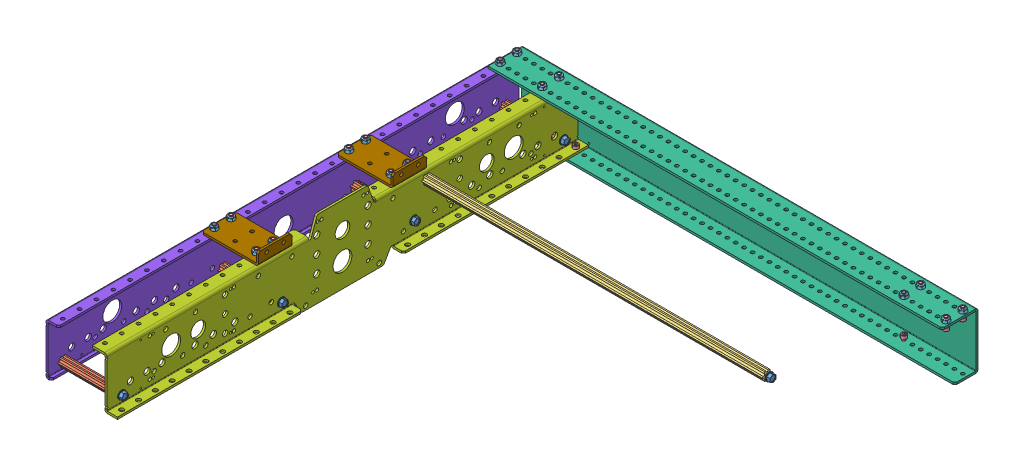
SolidWorks assembly AM14U3Square_Frame_Half, configuration Default. Lengths in mm.
Overall size (697.74 116.33 715.14).
56 component instances, 9 part files, 121 mates.
Components (placement in the parent):
- ThreadRollingScrew_0.25-20x0.75-1: ThreadRollingScrew_0.25-20x0.75 [FHTS 0.25-20-G-0.75-C] at (-600.075 -67.437 693.039) x (-1 0 0) z (0 0.924225 0.381849) size (24.64 12.19 12.19)
- ThreadRollingScrew_0.25-20x0.75-4: ThreadRollingScrew_0.25-20x0.75 [FHTS 0.25-20-G-0.75-C] at (-600.075 -67.437 26.035) x (-1 0 0) z (0 0.717495 0.696564) size (24.64 12.19 12.19)
- ThreadRollingScrew_0.25-20x0.75-5: ThreadRollingScrew_0.25-20x0.75 [FHTS 0.25-20-G-0.75-C] at (-692.15 -67.437 26.162) size (24.64 12.19 12.19)
- ThreadRollingScrew_0.25-20x0.75-7: ThreadRollingScrew_0.25-20x0.75 [FHTS 0.25-20-G-0.75-C] at (-603.25 -15.24 232.537) x (1 0 0) z (0 0.687398 0.726281) size (24.64 12.19 12.19)
- ThreadRollingScrew_0.25-20x0.75-9: ThreadRollingScrew_0.25-20x0.75 [FHTS 0.25-20-G-0.75-C] at (-692.15 -67.437 692.912) size (24.64 12.19 12.19)
- ThreadRollingScrew_0.25-20x0.75-10: ThreadRollingScrew_0.25-20x0.75 [FHTS 0.25-20-G-0.75-C] at (-82.55 -15.24 232.537) x (-1 0 0) z (0 0.525103 -0.851039) size (24.64 12.19 12.19)
- 500Churro_3.375-1: 500Churro_3.375 [Default] at (-603.25 -67.437 26.162) x (0 -0.866025 0.5) z (-1 0 0) size (14.66 12.7 85.72)
- 500Churro_3.375-2: 500Churro_3.375 [Default] at (-603.25 -67.437 692.912) x (0 -0.866025 0.5) z (-1 0 0) size (14.66 12.7 85.72)
- 500Churro_cut_20.25-1: 500Churro_cut_20.25 [Default] at (-85.725 -15.24 232.537) x (0 0 -1) z (-1 0 0) size (14.66 12.7 514.35)
- Screw_SHCS_10-32x0.5-19: Screw_SHCS_10-32x0.5 [HX-SHCS 0.19-32x1.375x1-C] at (-679.45 -11.176 42.037) x (0 1 0) z (0.542711 0 0.839919) size (17.53 7.94 7.94)
- Screw_SHCS_10-32x0.5-20: Screw_SHCS_10-32x0.5 [HX-SHCS 0.19-32x1.375x1-C] at (-679.45 -11.176 16.637) x (0 1 0) z (0.127767 0 0.991804) size (17.53 7.94 7.94)
- Screw_SHCS_10-32x0.5-21: Screw_SHCS_10-32x0.5 [HX-SHCS 0.19-32x1.375x1-C] at (-615.95 -11.176 16.637) x (0 1 0) z (0 0 1) size (17.53 7.94 7.94)
- Screw_SHCS_10-32x0.5-22: Screw_SHCS_10-32x0.5 [HX-SHCS 0.19-32x1.375x1-C] at (-615.95 -11.176 42.037) x (0 1 0) z (0.337423 0 -0.941353) size (17.53 7.94 7.94)
- Screw_SHCS_10-32x0.5-23: Screw_SHCS_10-32x0.5 [HX-SHCS 0.19-32x1.375x1-C] at (-590.55 -72.898 16.637) x (0 -1 0) z (0.717151 0 -0.696918) size (17.53 7.94 7.94)
- Screw_SHCS_10-32x0.5-24: Screw_SHCS_10-32x0.5 [HX-SHCS 0.19-32x1.375x1-C] at (-6.35 -11.176 16.637) x (0 1 0) z (0.222581 0 0.974914) size (17.53 7.94 7.94)
- Screw_SHCS_10-32x0.5-25: Screw_SHCS_10-32x0.5 [HX-SHCS 0.19-32x1.375x1-C] at (-6.35 -11.176 42.037) x (0 1 0) z (0.81526 0 0.579096) size (17.53 7.94 7.94)
- Screw_SHCS_10-32x0.5-26: Screw_SHCS_10-32x0.5 [HX-SHCS 0.19-32x1.375x1-C] at (-69.85 -11.176 16.637) x (0 1 0) z (0 0 1) size (17.53 7.94 7.94)
- Screw_SHCS_10-32x0.5-27: Screw_SHCS_10-32x0.5 [HX-SHCS 0.19-32x1.375x1-C] at (-69.85 -11.176 42.037) x (0 1 0) z (0.111454 0 0.99377) size (17.53 7.94 7.94)
- Screw_SHCS_10-32x0.5-28: Screw_SHCS_10-32x0.5 [HX-SHCS 0.19-32x1.375x1-C] at (-95.25 -73.406 16.637) x (0 -1 0) z (0.007214 0 0.999974) size (17.53 7.94 7.94)
- NylockNut_10-32-19: NylockNut_10-32 [Default] at (-679.45 0 42.037) x (0.996106 0 -0.088165) z (0 1 0) size (10.18 11.01 7.1)
- NylockNut_10-32-21: NylockNut_10-32 [Default] at (-679.45 0 16.637) x (1 0 0) z (0 1 0) size (10.18 11.01 7.1)
- NylockNut_10-32-22: NylockNut_10-32 [Default] at (-615.95 0 42.037) x (1 0 0) z (0 1 0) size (10.18 11.01 7.1)
- NylockNut_10-32-23: NylockNut_10-32 [Default] at (-615.95 0 16.637) x (-0.398852 0 -0.917015) z (0 1 0) size (10.18 11.01 7.1)
- NylockNut_10-32-25: NylockNut_10-32 [Default] at (-69.85 0 42.037) x (1 0 0) z (0 1 0) size (10.18 11.01 7.1)
- NylockNut_10-32-26: NylockNut_10-32 [Default] at (-69.85 0 16.637) x (1 0 0) z (0 1 0) size (10.18 11.01 7.1)
- NylockNut_10-32-27: NylockNut_10-32 [Default] at (-6.35 0 42.037) x (1 0 0) z (0 1 0) size (10.18 11.01 7.1)
- NylockNut_10-32-28: NylockNut_10-32 [Default] at (-6.35 0 16.637) x (1 0 0) z (0 1 0) size (10.18 11.01 7.1)
- NylockNut_10-32-29: NylockNut_10-32 [Default] at (-95.25 -84.582 16.637) x (1 0 0) z (0 -1 0) size (10.18 11.01 7.1)
- NylockNut_10-32-30: NylockNut_10-32 [Default] at (-590.55 -84.582 16.637) x (1 0 0) z (0 -1 0) size (10.18 11.01 7.1)
- Screw_SHCS_10-32x0.5-29: Screw_SHCS_10-32x0.5 [HX-SHCS 0.19-32x1.375x1-C] at (-679.45 -11.176 245.237) x (0 1 0) z (0.717626 0 0.696429) size (17.53 7.94 7.94)
- Screw_SHCS_10-32x0.5-30: Screw_SHCS_10-32x0.5 [HX-SHCS 0.19-32x1.375x1-C] at (-679.45 -11.176 270.637) x (0 1 0) z (-0.597439 0 0.801914) size (17.53 7.94 7.94)
- Screw_SHCS_10-32x0.5-31: Screw_SHCS_10-32x0.5 [HX-SHCS 0.19-32x1.375x1-C] at (-615.95 -11.176 245.237) x (0 1 0) z (0.931086 0 -0.3648) size (17.53 7.94 7.94)
- Screw_SHCS_10-32x0.5-32: Screw_SHCS_10-32x0.5 [HX-SHCS 0.19-32x1.375x1-C] at (-615.95 -11.176 270.637) x (0 1 0) z (0.782299 0 0.622903) size (17.53 7.94 7.94)
- Screw_SHCS_10-32x0.5-33: Screw_SHCS_10-32x0.5 [HX-SHCS 0.19-32x1.375x1-C] at (-615.95 -11.176 448.437) x (0 1 0) z (0 0 1) size (17.53 7.94 7.94)
- Screw_SHCS_10-32x0.5-34: Screw_SHCS_10-32x0.5 [HX-SHCS 0.19-32x1.375x1-C] at (-615.95 -11.176 473.837) x (0 1 0) z (0 0 1) size (17.53 7.94 7.94)
- Screw_SHCS_10-32x0.5-35: Screw_SHCS_10-32x0.5 [HX-SHCS 0.19-32x1.375x1-C] at (-679.45 -11.176 448.437) x (0 1 0) z (0 0 1) size (17.53 7.94 7.94)
- Screw_SHCS_10-32x0.5-36: Screw_SHCS_10-32x0.5 [HX-SHCS 0.19-32x1.375x1-C] at (-679.45 -11.176 473.837) x (0 1 0) z (0 0 1) size (17.53 7.94 7.94)
- NylockNut_10-32-31: NylockNut_10-32 [Default] at (-679.45 0 473.837) x (1 0 0) z (0 1 0) size (10.18 11.01 7.1)
- NylockNut_10-32-32: NylockNut_10-32 [Default] at (-679.45 0 448.437) x (1 0 0) z (0 1 0) size (10.18 11.01 7.1)
- NylockNut_10-32-33: NylockNut_10-32 [Default] at (-615.95 0 448.437) x (1 0 0) z (0 1 0) size (10.18 11.01 7.1)
- NylockNut_10-32-34: NylockNut_10-32 [Default] at (-615.95 0 473.837) x (1 0 0) z (0 1 0) size (10.18 11.01 7.1)
- NylockNut_10-32-35: NylockNut_10-32 [Default] at (-679.45 0 270.637) x (1 0 0) z (0 1 0) size (10.18 11.01 7.1)
- NylockNut_10-32-37: NylockNut_10-32 [Default] at (-679.45 0 245.237) x (1 0 0) z (0 1 0) size (10.18 11.01 7.1)
- NylockNut_10-32-38: NylockNut_10-32 [Default] at (-615.95 0 270.637) x (-0.99946 0 -0.032874) z (0 1 0) size (10.18 11.01 7.1)
- NylockNut_10-32-39: NylockNut_10-32 [Default] at (-615.95 0 245.237) x (-0.973817 0 0.227332) z (0 1 0) size (10.18 11.01 7.1)
- AM14U3EndPlate_Square-1: AM14U3EndPlate_Square [Default] at (-787.4 -81.407 0) x (1 0 0) z (0 -1 0) size (685.8 53.98 84.58)
- AM14U3InnerPlate_Square-1: AM14U3InnerPlate_Square [Default] at (-603.25 -76.962 765.937) x (0 0 -1) z (0 -1 0) size (711.2 38.1 116.33)
- AM14U3OuterPlate_Square-1: AM14U3OuterPlate_Square [Default] at (-667.7485 -26.7681 75.5865) x (0 0 1) z (0 -1 0) size (711.2 19.05 77.72)
- Bracket_2x3-1: Bracket_2x3 [Default] at (-685.8 -3.175 499.237) size (85.72 19.05 50.8)
- Bracket_2x3-2: Bracket_2x3 [Default] at (-685.8 -3.175 296.037) size (85.72 19.05 50.8)
- 500Churro_3.375-5: 500Churro_3.375 [Default] at (-688.975 -66.675 451.612) x (0 0 -1) z (1 0 0) size (14.66 12.7 85.72)
- 500Churro_3.375-6: 500Churro_3.375 [Default] at (-688.975 -59.4147 252.0115) x (0 0.995852 0.090991) z (1 0 0) size (14.66 12.7 85.72)
- ThreadRollingScrew_0.25-20x0.75-11: ThreadRollingScrew_0.25-20x0.75 [FHTS 0.25-20-G-0.75-C] at (-600.075 -66.675 451.612) x (-1 0 0) z (0 0.997671 0.06821) size (24.64 12.19 12.19)
- ThreadRollingScrew_0.25-20x0.75-12: ThreadRollingScrew_0.25-20x0.75 [FHTS 0.25-20-G-0.75-C] at (-600.075 -59.4147 252.0115) x (-1 0 0) z (0 -0.62596 0.779855) size (24.64 12.19 12.19)
- ThreadRollingScrew_0.25-20x0.75-13: ThreadRollingScrew_0.25-20x0.75 [FHTS 0.25-20-G-0.75-C] at (-692.15 -66.675 451.612) size (24.64 12.19 12.19)
- ThreadRollingScrew_0.25-20x0.75-14: ThreadRollingScrew_0.25-20x0.75 [FHTS 0.25-20-G-0.75-C] at (-692.15 -66.675 267.462) size (24.64 12.19 12.19)
Mates (geometry in assembly coordinates):
- Coincident1: coincident aligned: plane of AM14U3EndPlate_Square-1 through (0 0 53.975) normal (0 1 0); plane of assembly through (0 0 0) normal (0 1 0)
- Coincident2: coincident anti-aligned: plane of AM14U3EndPlate_Square-1 through (-787.4 -3.175 0) normal (0 0 -1); plane of assembly through (0 0 0) normal (0 0 1)
- Coincident3: coincident aligned: plane of AM14U3EndPlate_Square-1 through (0 -81.407 3.175) normal (1 0 0); plane of assembly through (0 0 0) normal (1 0 0)
- Concentric1: concentric anti-aligned: cylinder of AM14U3OuterPlate_Square-1 through (-679.45 -80.899 16.637) axis (0 1 0) radius 2.667; cylinder of AM14U3EndPlate_Square-1 through (-679.45 0 16.637) axis (0 -1 0) radius 2.667
- Concentric2: concentric aligned: cylinder of AM14U3OuterPlate_Square-1 through (-679.45 -80.899 42.037) axis (0 1 0) radius 2.667; cylinder of AM14U3EndPlate_Square-1 through (-679.45 -5.08 42.037) axis (0 1 0) radius 2.667
- Concentric3: concentric anti-aligned: cylinder of AM14U3InnerPlate_Square-1 through (-615.95 -80.899 16.637) axis (0 1 0) radius 2.667; cylinder of AM14U3EndPlate_Square-1 through (-615.95 0 16.637) axis (0 -1 0) radius 2.667
- Concentric4: concentric aligned: cylinder of AM14U3InnerPlate_Square-1 through (-615.95 -80.899 448.437) axis (0 1 0) radius 2.667; cylinder of Bracket_2x3-1 through (-615.95 -3.175 448.437) axis (0 1 0) radius 2.667
- Coincident7: coincident aligned: cylinder of AM14U3InnerPlate_Square-1 through (-615.95 -80.899 473.837) axis (0 1 0) radius 2.667; circle of Bracket_2x3-1
- Coincident8: coincident anti-aligned: plane of AM14U3InnerPlate_Square-1 through (-603.25 -3.175 -46.863) normal (0 1 0); plane of Bracket_2x3-1 through (-685.8 -3.175 435.737) normal (0 -1 0)
- Concentric5: concentric anti-aligned: circle of AM14U3InnerPlate_Square-1; cylinder of Bracket_2x3-2 through (-615.95 -3.175 270.637) axis (0 1 0) radius 2.667
- Concentric6: concentric anti-aligned: circle of AM14U3InnerPlate_Square-1; cylinder of Bracket_2x3-2 through (-615.95 -3.175 245.237) axis (0 1 0) radius 2.667
- Coincident9: coincident anti-aligned: plane of AM14U3InnerPlate_Square-1 through (-603.25 -3.175 -46.863) normal (0 1 0); plane of Bracket_2x3-2 through (-685.8 -3.175 232.537) normal (0 -1 0)
- Concentric25: concentric anti-aligned: cylinder of AM14U3OuterPlate_Square-1 through (-673.1 -67.437 26.162) axis (-1 0 0) radius 3.3528; cylinder of 500Churro_3.375-1 through (-688.975 -67.437 26.162) axis (1 0 0) radius 2.9337
- Concentric26: concentric anti-aligned: cylinder of AM14U3OuterPlate_Square-1 through (-673.1 -67.437 692.912) axis (-1 0 0) radius 3.3528; cylinder of 500Churro_3.375-2 through (-688.975 -67.437 692.912) axis (1 0 0) radius 2.9337
- Coincident28: coincident anti-aligned: plane of AM14U3OuterPlate_Square-1 through (-688.975 -7.112 -46.863) normal (1 0 0); plane of 500Churro_3.375-2 through (-688.975 -70.612 698.4113) normal (-1 0 0)
- Parallel1: parallel aligned: plane of AM14U3OuterPlate_Square-1 through (-688.975 -80.899 765.937) normal (0 -1 0); plane of 500Churro_3.375-2 through (-688.975 -73.787 689.2458) normal (0 -1 0)
- Coincident30: coincident anti-aligned: plane of AM14U3OuterPlate_Square-1 through (-688.975 -7.112 -46.863) normal (1 0 0); plane of 500Churro_3.375-1 through (-688.975 -70.612 31.6613) normal (-1 0 0)
- Parallel2: parallel aligned: plane of AM14U3OuterPlate_Square-1 through (-688.975 -80.899 765.937) normal (0 -1 0); plane of 500Churro_3.375-1 through (-688.975 -73.787 22.4958) normal (0 -1 0)
- Concentric29: concentric anti-aligned: cylinder of AM14U3InnerPlate_Square-1 through (-584.2 -15.24 232.537) axis (-1 0 0) radius 3.3528; cylinder of 500Churro_cut_20.25-1 through (-600.075 -15.24 232.537) axis (1 0 0) radius 2.9337
- Coincident37: coincident anti-aligned: plane of AM14U3InnerPlate_Square-1 through (-600.075 -7.112 765.937) normal (1 0 0); plane of 500Churro_cut_20.25-1 through (-600.075 -18.415 227.0377) normal (-1 0 0)
- Concentric301: concentric aligned: cylinder of AM14U3InnerPlate_Square-1 through (-622.3 -67.437 693.039) axis (1 0 0) radius 3.3528; cylinder of ThreadRollingScrew_0.25-20x0.75-1 through (-600.075 -67.437 693.039) axis (1 0 0) radius 3.175
- Coincident381: coincident anti-aligned: plane of AM14U3InnerPlate_Square-1 through (-600.075 -7.112 765.937) normal (1 0 0); plane of ThreadRollingScrew_0.25-20x0.75-1 through (-600.075 -68.6494 695.9734) normal (-1 0 0)
- Concentric331: concentric aligned: cylinder of AM14U3InnerPlate_Square-1 through (-622.3 -67.437 26.035) axis (1 0 0) radius 3.3528; cylinder of ThreadRollingScrew_0.25-20x0.75-4 through (-600.075 -67.437 26.035) axis (1 0 0) radius 3.175
- Coincident411: coincident anti-aligned: plane of AM14U3InnerPlate_Square-1 through (-600.075 -7.112 765.937) normal (1 0 0); plane of ThreadRollingScrew_0.25-20x0.75-4 through (-600.075 -69.6486 28.313) normal (-1 0 0)
- Concentric341: concentric aligned: cylinder of AM14U3OuterPlate_Square-1 through (-673.1 -67.437 26.162) axis (-1 0 0) radius 3.3528; cylinder of ThreadRollingScrew_0.25-20x0.75-5 through (-692.15 -67.437 26.162) axis (-1 0 0) radius 3.175
- Coincident421: coincident anti-aligned: plane of AM14U3OuterPlate_Square-1 through (-692.15 -7.112 -46.863) normal (-1 0 0); plane of ThreadRollingScrew_0.25-20x0.75-5 through (-692.15 -64.262 26.162) normal (1 0 0)
- Concentric361: concentric aligned: cylinder of AM14U3InnerPlate_Square-1 through (-584.2 -15.24 232.537) axis (-1 0 0) radius 3.3528; cylinder of ThreadRollingScrew_0.25-20x0.75-7 through (-603.25 -15.24 232.537) axis (-1 0 0) radius 3.175
- Coincident441: coincident anti-aligned: plane of AM14U3InnerPlate_Square-1 through (-603.25 -7.112 765.937) normal (-1 0 0); plane of ThreadRollingScrew_0.25-20x0.75-7 through (-603.25 -12.9341 230.3545) normal (1 0 0)
- Concentric381: concentric aligned: cylinder of AM14U3OuterPlate_Square-1 through (-673.1 -67.437 692.912) axis (-1 0 0) radius 3.3528; cylinder of ThreadRollingScrew_0.25-20x0.75-9 through (-692.15 -67.437 692.912) axis (-1 0 0) radius 3.175
- Coincident461: coincident anti-aligned: plane of AM14U3OuterPlate_Square-1 through (-692.15 -7.112 -46.863) normal (-1 0 0); plane of ThreadRollingScrew_0.25-20x0.75-9 through (-692.15 -64.262 692.912) normal (1 0 0)
- Concentric39: concentric aligned: cylinder of 500Churro_cut_20.25-1 through (-600.075 -15.24 232.537) axis (1 0 0) radius 2.9337; cylinder of ThreadRollingScrew_0.25-20x0.75-10 through (-82.55 -15.24 232.537) axis (1 0 0) radius 3.175
- Distance4: distance = 3.175 mm anti-aligned: plane of 500Churro_cut_20.25-1 through (-85.725 -18.415 227.0377) normal (1 0 0); plane of ThreadRollingScrew_0.25-20x0.75-10 through (-82.55 -12.538 234.2042) normal (-1 0 0)
- Parallel5: parallel aligned: plane of AM14U3InnerPlate_Square-1 through (-603.25 -3.175 -46.863) normal (0 1 0); plane of 500Churro_cut_20.25-1 through (-600.075 -8.89 230.9495) normal (0 1 0)
- Concentric4721: concentric anti-aligned: cylinder of AM14U3OuterPlate_Square-1 through (-679.45 -80.899 42.037) axis (0 1 0) radius 2.667; cylinder of Screw_SHCS_10-32x0.5-19 through (-679.45 -42.926 42.037) axis (0 -1 0) radius 3.9688
- Coincident5621: coincident anti-aligned: plane of AM14U3OuterPlate_Square-1 through (-688.975 -6.35 765.937) normal (0 -1 0); plane of Screw_SHCS_10-32x0.5-19 through (-682.7834 -6.35 44.1909) normal (0 1 0)
- Concentric4731: concentric anti-aligned: cylinder of AM14U3OuterPlate_Square-1 through (-679.45 -80.899 16.637) axis (0 1 0) radius 2.667; cylinder of Screw_SHCS_10-32x0.5-20 through (-679.45 -42.926 16.637) axis (0 -1 0) radius 3.9688
- Coincident5631: coincident anti-aligned: plane of AM14U3OuterPlate_Square-1 through (-688.975 -6.35 765.937) normal (0 -1 0); plane of Screw_SHCS_10-32x0.5-20 through (-683.3862 -6.35 17.1441) normal (0 1 0)
- Concentric4741: concentric anti-aligned: cylinder of AM14U3InnerPlate_Square-1 through (-615.95 -80.899 16.637) axis (0 1 0) radius 2.667; cylinder of Screw_SHCS_10-32x0.5-21 through (-615.95 -42.926 16.637) axis (0 -1 0) radius 3.9688
- Coincident5641: coincident anti-aligned: plane of AM14U3InnerPlate_Square-1 through (-603.25 -6.35 -46.863) normal (0 -1 0); plane of Screw_SHCS_10-32x0.5-21 through (-619.9187 -6.35 16.637) normal (0 1 0)
- Concentric4751: concentric anti-aligned: cylinder of AM14U3InnerPlate_Square-1 through (-615.95 -80.899 42.037) axis (0 1 0) radius 2.667; cylinder of Screw_SHCS_10-32x0.5-22 through (-615.95 -42.926 42.037) axis (0 -1 0) radius 3.9688
- Coincident5651: coincident anti-aligned: plane of AM14U3InnerPlate_Square-1 through (-603.25 -6.35 -46.863) normal (0 -1 0); plane of Screw_SHCS_10-32x0.5-22 through (-612.214 -6.35 43.3761) normal (0 1 0)
- Concentric4761: concentric aligned: cylinder of Screw_SHCS_10-32x0.5-23 through (-590.55 -41.148 16.637) axis (0 1 0) radius 3.9688; cylinder of AM14U3InnerPlate_Square-1 through (-590.55 -80.899 16.637) axis (0 1 0) radius 3.3528
- Coincident5661: coincident anti-aligned: plane of AM14U3InnerPlate_Square-1 through (-600.075 -77.724 -46.863) normal (0 1 0); plane of Screw_SHCS_10-32x0.5-23 through (-593.3159 -77.724 13.7908) normal (0 -1 0)
- Concentric478: concentric aligned: cylinder of Screw_SHCS_10-32x0.5-24 through (-6.35 -42.926 16.637) axis (0 -1 0) radius 2.413; cylinder of AM14U3EndPlate_Square-1 through (-6.35 0 16.637) axis (0 -1 0) radius 2.667
- Concentric479: concentric anti-aligned: cylinder of Screw_SHCS_10-32x0.5-25 through (-6.35 -42.926 42.037) axis (0 -1 0) radius 2.413; cylinder of AM14U3EndPlate_Square-1 through (-6.35 -5.08 42.037) axis (0 1 0) radius 2.667
- Coincident567: coincident aligned: plane of Screw_SHCS_10-32x0.5-24 through (-10.2192 -6.35 17.5204) normal (0 1 0); plane of Screw_SHCS_10-32x0.5-25 through (-8.6483 -6.35 45.2726) normal (0 1 0)
- Concentric480: concentric aligned: cylinder of Screw_SHCS_10-32x0.5-26 through (-69.85 -42.926 16.637) axis (0 -1 0) radius 2.413; cylinder of AM14U3EndPlate_Square-1 through (-69.85 0 16.637) axis (0 -1 0) radius 2.667
- Concentric481: concentric anti-aligned: cylinder of Screw_SHCS_10-32x0.5-27 through (-69.85 -42.926 42.037) axis (0 -1 0) radius 2.413; cylinder of AM14U3EndPlate_Square-1 through (-69.85 -5.08 42.037) axis (0 1 0) radius 2.667
- Coincident568: coincident aligned: plane of Screw_SHCS_10-32x0.5-26 through (-73.8188 -6.35 16.637) normal (0 1 0); plane of Screw_SHCS_10-32x0.5-27 through (-73.794 -6.35 42.4793) normal (0 1 0)
- Coincident569: coincident aligned: plane of Screw_SHCS_10-32x0.5-25 through (-8.6483 -6.35 45.2726) normal (0 1 0); plane of Screw_SHCS_10-32x0.5-27 through (-73.794 -6.35 42.4793) normal (0 1 0)
- Distance5: distance = 3.175 mm anti-aligned: plane of AM14U3EndPlate_Square-1 through (0 -3.175 53.975) normal (0 -1 0); plane of Screw_SHCS_10-32x0.5-27 through (-73.794 -6.35 42.4793) normal (0 1 0)
- Concentric482: concentric anti-aligned: cylinder of Screw_SHCS_10-32x0.5-28 through (-95.25 -41.656 16.637) axis (0 1 0) radius 2.413; cylinder of AM14U3EndPlate_Square-1 through (-95.25 0 16.637) axis (0 -1 0) radius 2.667
- Distance6: distance = 3.175 mm anti-aligned: plane of AM14U3EndPlate_Square-1 through (-787.4 -81.407 34.925) normal (0 1 0); plane of Screw_SHCS_10-32x0.5-28 through (-91.2814 -78.232 16.6084) normal (0 -1 0)
- Concentric4831: concentric anti-aligned: cylinder of NylockNut_10-32-19 through (-679.45 5.9531 42.037) axis (0 1 0) radius 2.0193; cylinder of Screw_SHCS_10-32x0.5-19 through (-679.45 -42.926 42.037) axis (0 -1 0) radius 2.413
- Coincident5721: coincident anti-aligned: plane of AM14U3EndPlate_Square-1 through (0 0 53.975) normal (0 1 0); plane of NylockNut_10-32-19 through (-679.45 0 42.037) normal (0 -1 0)
- Concentric4841: concentric anti-aligned: cylinder of NylockNut_10-32-21 through (-679.45 5.9531 16.637) axis (0 1 0) radius 2.0193; cylinder of Screw_SHCS_10-32x0.5-20 through (-679.45 -42.926 16.637) axis (0 -1 0) radius 2.413
- Coincident5731: coincident anti-aligned: plane of AM14U3EndPlate_Square-1 through (0 0 53.975) normal (0 1 0); plane of NylockNut_10-32-21 through (-679.45 0 16.637) normal (0 -1 0)
- Concentric4851: concentric anti-aligned: cylinder of NylockNut_10-32-22 through (-615.95 5.9531 42.037) axis (0 1 0) radius 2.0193; cylinder of Screw_SHCS_10-32x0.5-22 through (-615.95 -42.926 42.037) axis (0 -1 0) radius 2.413
- Coincident5741: coincident anti-aligned: plane of AM14U3EndPlate_Square-1 through (0 0 53.975) normal (0 1 0); plane of NylockNut_10-32-22 through (-615.95 0 42.037) normal (0 -1 0)
- Concentric4861: concentric anti-aligned: cylinder of NylockNut_10-32-23 through (-615.95 5.9531 16.637) axis (0 1 0) radius 2.0193; cylinder of Screw_SHCS_10-32x0.5-21 through (-615.95 -42.926 16.637) axis (0 -1 0) radius 2.413
- Coincident5751: coincident anti-aligned: plane of AM14U3EndPlate_Square-1 through (0 0 53.975) normal (0 1 0); plane of NylockNut_10-32-23 through (-615.95 0 16.637) normal (0 -1 0)
- Concentric4871: concentric anti-aligned: cylinder of NylockNut_10-32-25 through (-69.85 5.9531 42.037) axis (0 1 0) radius 2.0193; cylinder of Screw_SHCS_10-32x0.5-27 through (-69.85 -42.926 42.037) axis (0 -1 0) radius 2.413
- Coincident5771: coincident anti-aligned: plane of AM14U3EndPlate_Square-1 through (0 0 53.975) normal (0 1 0); plane of NylockNut_10-32-25 through (-69.85 0 42.037) normal (0 -1 0)
- Concentric4881: concentric anti-aligned: cylinder of NylockNut_10-32-26 through (-69.85 5.9531 16.637) axis (0 1 0) radius 2.0193; cylinder of Screw_SHCS_10-32x0.5-26 through (-69.85 -42.926 16.637) axis (0 -1 0) radius 2.413
- Coincident5781: coincident anti-aligned: plane of AM14U3EndPlate_Square-1 through (0 0 53.975) normal (0 1 0); plane of NylockNut_10-32-26 through (-69.85 0 16.637) normal (0 -1 0)
- Concentric4891: concentric anti-aligned: cylinder of NylockNut_10-32-27 through (-6.35 5.9531 42.037) axis (0 1 0) radius 2.0193; cylinder of Screw_SHCS_10-32x0.5-25 through (-6.35 -42.926 42.037) axis (0 -1 0) radius 2.413
- Coincident5791: coincident anti-aligned: plane of AM14U3EndPlate_Square-1 through (0 0 53.975) normal (0 1 0); plane of NylockNut_10-32-27 through (-6.35 0 42.037) normal (0 -1 0)
- Concentric4901: concentric anti-aligned: cylinder of NylockNut_10-32-28 through (-6.35 5.9531 16.637) axis (0 1 0) radius 2.0193; cylinder of Screw_SHCS_10-32x0.5-24 through (-6.35 -42.926 16.637) axis (0 -1 0) radius 2.413
- Coincident5801: coincident anti-aligned: plane of AM14U3EndPlate_Square-1 through (0 0 53.975) normal (0 1 0); plane of NylockNut_10-32-28 through (-6.35 0 16.637) normal (0 -1 0)
- Concentric4911: concentric anti-aligned: cylinder of NylockNut_10-32-29 through (-95.25 -90.5351 16.637) axis (0 -1 0) radius 2.0193; cylinder of Screw_SHCS_10-32x0.5-28 through (-95.25 -41.656 16.637) axis (0 1 0) radius 2.413
- Coincident5811: coincident anti-aligned: plane of AM14U3EndPlate_Square-1 through (-787.4 -84.582 34.925) normal (0 -1 0); plane of NylockNut_10-32-29 through (-95.25 -84.582 16.637) normal (0 1 0)
- Concentric4921: concentric anti-aligned: cylinder of NylockNut_10-32-30 through (-590.55 -90.5351 16.637) axis (0 -1 0) radius 2.0193; cylinder of Screw_SHCS_10-32x0.5-23 through (-590.55 -41.148 16.637) axis (0 1 0) radius 2.413
- Coincident5821: coincident anti-aligned: plane of AM14U3EndPlate_Square-1 through (-787.4 -84.582 34.925) normal (0 -1 0); plane of NylockNut_10-32-30 through (-590.55 -84.582 16.637) normal (0 1 0)
- Concentric4931: concentric anti-aligned: cylinder of AM14U3OuterPlate_Square-1 through (-679.45 -80.899 245.237) axis (0 1 0) radius 2.667; cylinder of Screw_SHCS_10-32x0.5-29 through (-679.45 -42.926 245.237) axis (0 -1 0) radius 3.9688
- Coincident5831: coincident anti-aligned: plane of AM14U3OuterPlate_Square-1 through (-688.975 -6.35 765.937) normal (0 -1 0); plane of Screw_SHCS_10-32x0.5-29 through (-682.214 -6.35 248.0851) normal (0 1 0)
- Concentric4941: concentric anti-aligned: cylinder of AM14U3OuterPlate_Square-1 through (-679.45 -80.899 270.637) axis (0 1 0) radius 2.667; cylinder of Screw_SHCS_10-32x0.5-30 through (-679.45 -42.926 270.637) axis (0 -1 0) radius 3.9688
- Coincident5841: coincident anti-aligned: plane of AM14U3OuterPlate_Square-1 through (-688.975 -6.35 765.937) normal (0 -1 0); plane of Screw_SHCS_10-32x0.5-30 through (-682.6326 -6.35 268.2659) normal (0 1 0)
- Concentric4951: concentric aligned: circle of AM14U3InnerPlate_Square-1; cylinder of Screw_SHCS_10-32x0.5-31 through (-615.95 -42.926 245.237) axis (0 -1 0) radius 3.9688
- Coincident5851: coincident anti-aligned: plane of AM14U3InnerPlate_Square-1 through (-603.25 -6.35 -46.863) normal (0 -1 0); plane of Screw_SHCS_10-32x0.5-31 through (-614.5022 -6.35 248.9322) normal (0 1 0)
- Concentric4961: concentric aligned: circle of AM14U3InnerPlate_Square-1; cylinder of Screw_SHCS_10-32x0.5-32 through (-615.95 -42.926 270.637) axis (0 -1 0) radius 3.9688
- Coincident5861: coincident anti-aligned: plane of AM14U3InnerPlate_Square-1 through (-603.25 -6.35 -46.863) normal (0 -1 0); plane of Screw_SHCS_10-32x0.5-32 through (-618.4221 -6.35 273.7418) normal (0 1 0)
- Concentric4971: concentric anti-aligned: cylinder of AM14U3InnerPlate_Square-1 through (-615.95 -80.899 448.437) axis (0 1 0) radius 2.667; cylinder of Screw_SHCS_10-32x0.5-33 through (-615.95 -42.926 448.437) axis (0 -1 0) radius 3.9688
- Coincident5871: coincident anti-aligned: plane of AM14U3InnerPlate_Square-1 through (-603.25 -6.35 -46.863) normal (0 -1 0); plane of Screw_SHCS_10-32x0.5-33 through (-619.9187 -6.35 448.437) normal (0 1 0)
- Concentric4981: concentric anti-aligned: cylinder of Screw_SHCS_10-32x0.5-34 through (-615.95 -42.926 473.837) axis (0 -1 0) radius 3.9688; cylinder of AM14U3InnerPlate_Square-1 through (-615.95 -80.899 473.837) axis (0 1 0) radius 2.667
- Coincident5881: coincident anti-aligned: plane of AM14U3InnerPlate_Square-1 through (-603.25 -6.35 -46.863) normal (0 -1 0); plane of Screw_SHCS_10-32x0.5-34 through (-619.9187 -6.35 473.837) normal (0 1 0)
- Concentric4991: concentric anti-aligned: cylinder of AM14U3OuterPlate_Square-1 through (-679.45 -80.899 448.437) axis (0 1 0) radius 2.667; cylinder of Screw_SHCS_10-32x0.5-35 through (-679.45 -42.926 448.437) axis (0 -1 0) radius 3.9688
- Coincident5891: coincident anti-aligned: plane of AM14U3OuterPlate_Square-1 through (-688.975 -6.35 765.937) normal (0 -1 0); plane of Screw_SHCS_10-32x0.5-35 through (-683.4187 -6.35 448.437) normal (0 1 0)
- Concentric5001: concentric anti-aligned: cylinder of AM14U3OuterPlate_Square-1 through (-679.45 -80.899 473.837) axis (0 1 0) radius 2.667; cylinder of Screw_SHCS_10-32x0.5-36 through (-679.45 -42.926 473.837) axis (0 -1 0) radius 3.9688
- Coincident5901: coincident anti-aligned: plane of AM14U3OuterPlate_Square-1 through (-688.975 -6.35 765.937) normal (0 -1 0); plane of Screw_SHCS_10-32x0.5-36 through (-683.4187 -6.35 473.837) normal (0 1 0)
- Concentric5011: concentric aligned: cylinder of Bracket_2x3-1 through (-679.45 -3.175 473.837) axis (0 1 0) radius 2.667; cylinder of NylockNut_10-32-31 through (-679.45 5.9531 473.837) axis (0 1 0) radius 2.0193
- Coincident5911: coincident anti-aligned: plane of Bracket_2x3-1 through (-685.8 0 435.737) normal (0 1 0); plane of NylockNut_10-32-31 through (-679.45 0 473.837) normal (0 -1 0)
- Concentric5021: concentric aligned: cylinder of Bracket_2x3-1 through (-679.45 -3.175 448.437) axis (0 1 0) radius 2.667; cylinder of NylockNut_10-32-32 through (-679.45 5.9531 448.437) axis (0 1 0) radius 2.0193
- Coincident5921: coincident anti-aligned: plane of Bracket_2x3-1 through (-685.8 0 435.737) normal (0 1 0); plane of NylockNut_10-32-32 through (-679.45 0 448.437) normal (0 -1 0)
- Concentric5031: concentric aligned: cylinder of Bracket_2x3-1 through (-615.95 -3.175 448.437) axis (0 1 0) radius 2.667; cylinder of NylockNut_10-32-33 through (-615.95 5.9531 448.437) axis (0 1 0) radius 2.0193
- Coincident5931: coincident anti-aligned: plane of Bracket_2x3-1 through (-685.8 0 435.737) normal (0 1 0); plane of NylockNut_10-32-33 through (-615.95 0 448.437) normal (0 -1 0)
- Concentric5041: concentric aligned: cylinder of Bracket_2x3-1 through (-615.95 -3.175 473.837) axis (0 1 0) radius 2.667; cylinder of NylockNut_10-32-34 through (-615.95 5.9531 473.837) axis (0 1 0) radius 2.0193
- Coincident5941: coincident anti-aligned: plane of Bracket_2x3-1 through (-685.8 0 435.737) normal (0 1 0); plane of NylockNut_10-32-34 through (-615.95 0 473.837) normal (0 -1 0)
- Concentric5051: concentric aligned: cylinder of Bracket_2x3-2 through (-679.45 -3.175 270.637) axis (0 1 0) radius 2.667; cylinder of NylockNut_10-32-35 through (-679.45 5.9531 270.637) axis (0 1 0) radius 2.0193
- Coincident5951: coincident anti-aligned: plane of Bracket_2x3-2 through (-685.8 0 232.537) normal (0 1 0); plane of NylockNut_10-32-35 through (-679.45 0 270.637) normal (0 -1 0)
- Concentric5061: concentric aligned: cylinder of Bracket_2x3-2 through (-679.45 -3.175 245.237) axis (0 1 0) radius 2.667; cylinder of NylockNut_10-32-37 through (-679.45 5.9531 245.237) axis (0 1 0) radius 2.0193
- Coincident5961: coincident anti-aligned: plane of Bracket_2x3-2 through (-685.8 0 232.537) normal (0 1 0); plane of NylockNut_10-32-37 through (-679.45 0 245.237) normal (0 -1 0)
- Concentric5071: concentric aligned: cylinder of Bracket_2x3-2 through (-615.95 -3.175 270.637) axis (0 1 0) radius 2.667; cylinder of NylockNut_10-32-38 through (-615.95 5.9531 270.637) axis (0 1 0) radius 2.0193
- Coincident5971: coincident anti-aligned: plane of Bracket_2x3-2 through (-685.8 0 232.537) normal (0 1 0); plane of NylockNut_10-32-38 through (-615.95 0 270.637) normal (0 -1 0)
- Concentric5081: concentric aligned: cylinder of Bracket_2x3-2 through (-615.95 -3.175 245.237) axis (0 1 0) radius 2.667; cylinder of NylockNut_10-32-39 through (-615.95 5.9531 245.237) axis (0 1 0) radius 2.0193
- Coincident5981: coincident anti-aligned: plane of Bracket_2x3-2 through (-685.8 0 232.537) normal (0 1 0); plane of NylockNut_10-32-39 through (-615.95 0 245.237) normal (0 -1 0)
- Concentric5082: concentric anti-aligned: cylinder of AM14U3InnerPlate_Square-1 through (-622.3 -66.675 451.612) axis (1 0 0) radius 3.3528; cylinder of 500Churro_3.375-5 through (-603.25 -66.675 451.612) axis (-1 0 0) radius 2.9337
- Concentric5083: concentric anti-aligned: cylinder of AM14U3InnerPlate_Square-1 through (-622.3 -59.4147 252.0115) axis (1 0 0) radius 3.3528; cylinder of 500Churro_3.375-6 through (-603.25 -59.4147 252.0115) axis (-1 0 0) radius 2.9337
- Coincident5982: coincident aligned: plane of 500Churro_3.375-5 through (-603.25 -63.5 446.1127) normal (1 0 0); plane of 500Churro_3.375-6 through (-603.25 -54.2272 255.6737) normal (1 0 0)
- Coincident5983: coincident anti-aligned: plane of AM14U3InnerPlate_Square-1 through (-603.25 -7.112 765.937) normal (-1 0 0); plane of 500Churro_3.375-5 through (-603.25 -63.5 446.1127) normal (1 0 0)
- Concentric50841: concentric aligned: cylinder of AM14U3InnerPlate_Square-1 through (-622.3 -66.675 451.612) axis (1 0 0) radius 3.3528; cylinder of ThreadRollingScrew_0.25-20x0.75-11 through (-600.075 -66.675 451.612) axis (1 0 0) radius 3.175
- Coincident59841: coincident anti-aligned: plane of AM14U3InnerPlate_Square-1 through (-600.075 -7.112 765.937) normal (1 0 0); plane of ThreadRollingScrew_0.25-20x0.75-11 through (-600.075 -66.8916 454.7796) normal (-1 0 0)
- Concentric50851: concentric aligned: cylinder of AM14U3InnerPlate_Square-1 through (-622.3 -59.4147 252.0115) axis (1 0 0) radius 3.3528; cylinder of ThreadRollingScrew_0.25-20x0.75-12 through (-600.075 -59.4147 252.0115) axis (1 0 0) radius 3.175
- Coincident59851: coincident anti-aligned: plane of AM14U3InnerPlate_Square-1 through (-600.075 -7.112 765.937) normal (1 0 0); plane of ThreadRollingScrew_0.25-20x0.75-12 through (-600.075 -61.8908 250.0241) normal (-1 0 0)
- Concentric50861: concentric aligned: cylinder of AM14U3OuterPlate_Square-1 through (-673.1 -66.675 451.612) axis (-1 0 0) radius 3.3782; cylinder of ThreadRollingScrew_0.25-20x0.75-13 through (-692.15 -66.675 451.612) axis (-1 0 0) radius 3.175
- Coincident59861: coincident anti-aligned: plane of AM14U3OuterPlate_Square-1 through (-692.15 -7.112 -46.863) normal (-1 0 0); plane of ThreadRollingScrew_0.25-20x0.75-13 through (-692.15 -63.5 451.612) normal (1 0 0)
- Concentric50871: concentric aligned: cylinder of AM14U3OuterPlate_Square-1 through (-673.1 -66.675 267.462) axis (-1 0 0) radius 3.3782; cylinder of ThreadRollingScrew_0.25-20x0.75-14 through (-692.15 -66.675 267.462) axis (-1 0 0) radius 3.175
- Coincident59871: coincident anti-aligned: plane of AM14U3OuterPlate_Square-1 through (-692.15 -7.112 -46.863) normal (-1 0 0); plane of ThreadRollingScrew_0.25-20x0.75-14 through (-692.15 -63.5 267.462) normal (1 0 0)
- Concentric50872: concentric anti-aligned: cylinder of Screw_SHCS_10-32x0.5-22 through (-615.95 -42.926 42.037) axis (0 -1 0) radius 2.413; cylinder of AM14U3EndPlate_Square-1 through (-615.95 -5.08 42.037) axis (0 1 0) radius 2.667
- Coincident59872: coincident anti-aligned: plane of AM14U3EndPlate_Square-1 through (0 -3.175 53.975) normal (0 -1 0); plane of AM14U3InnerPlate_Square-1 through (-603.25 -3.175 -46.863) normal (0 1 0)
- Coincident59873: coincident anti-aligned: plane of AM14U3EndPlate_Square-1 through (0 -3.175 53.975) normal (0 -1 0); plane of AM14U3OuterPlate_Square-1 through (-688.975 -3.175 765.937) normal (0 1 0)
- Concentric50873: concentric anti-aligned: cylinder of Screw_SHCS_10-32x0.5-34 through (-615.95 -42.926 473.837) axis (0 -1 0) radius 2.413; cylinder of NylockNut_10-32-34 through (-615.95 5.9531 473.837) axis (0 1 0) radius 2.0193
